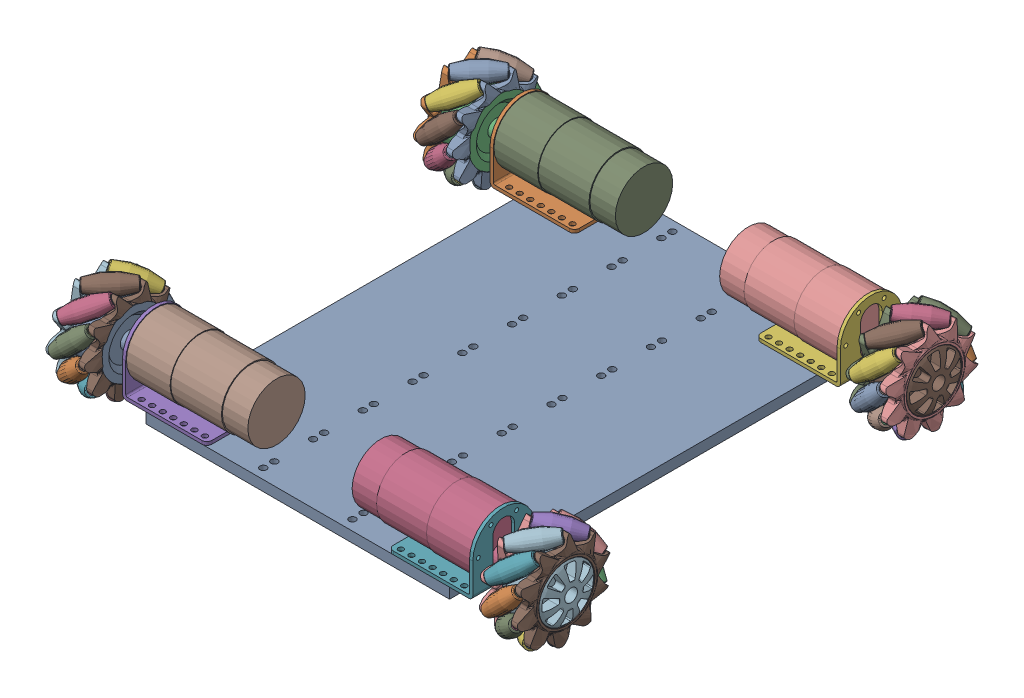
SolidWorks assembly ChassisRev2, configuration Default. Lengths in mm.
Overall size (295.62 86.39 309.14).
13 component instances, 4 part files, 32 mates.
Components (placement in the parent):
- BasePlateLayoutRev2-1: BasePlateLayoutRev2 [Default] at origin size (184.15 6.35 260.35)
- 37D bracket -1: 37D bracket  [Default] at (-106.2055 0 -111.4) size (51.2 39.6 37.6)
- Mecanum Wheel Right-1: Mecanum Wheel Right [Default] at (-111.8327 3.9469 -59.297) x (1 0 0) z (0 -0.102615 -0.994721) size (34.3 61.34 61.21)
- Motor - 37D - with encoder - 100_1 and 131_1-1: Motor - 37D - with encoder - 100_1 and 131_1 [Default] at (31.6055 20.8 111.4) x (0 0 -1) z (1 0 0) size (36.8 36.8 94.6)
- 37D bracket -2: 37D bracket  [Default] at (-106.2055 0 111.4) size (51.2 39.6 37.6)
- 37D bracket -3: 37D bracket  [Default] at (106.2055 0 -111.4) x (-1 0 0) z (0 0 -1) size (51.2 39.6 37.6)
- 37D bracket -4: 37D bracket  [Default] at (106.2055 0 111.4) x (-1 0 0) z (0 0 -1) size (51.2 39.6 37.6)
- Motor - 37D - with encoder - 100_1 and 131_1-2: Motor - 37D - with encoder - 100_1 and 131_1 [Default] at (-31.6055 20.8 111.4) x (0 0 1) z (-1 0 0) size (36.8 36.8 94.6)
- Motor - 37D - with encoder - 100_1 and 131_1-3: Motor - 37D - with encoder - 100_1 and 131_1 [Default] at (-31.6055 20.8 -111.4) x (0 0 1) z (-1 0 0) size (36.8 36.8 94.6)
- Motor - 37D - with encoder - 100_1 and 131_1-4: Motor - 37D - with encoder - 100_1 and 131_1 [Default] at (31.6055 20.8 -111.4) x (0 0 -1) z (1 0 0) size (36.8 36.8 94.6)
- Mecanum Wheel Right-2: Mecanum Wheel Right [Default] at (111.8327 -30.2853 -140.8668) x (-1 0 0) z (0 0.637998 0.770038) size (34.3 61.34 61.21)
- Mecanum Wheel Right-3: Mecanum Wheel Right [Default] at (111.8327 -34.6568 89.8655) x (-1 0 0) z (0 0.759736 0.650232) size (34.3 61.34 61.21)
- Mecanum Wheel Right-4: Mecanum Wheel Right [Default] at (-111.8327 2.6629 163.2437) x (1 0 0) z (0 -0.078013 -0.996952) size (34.3 61.34 61.21)
Mates (geometry in assembly coordinates):
- Concentric2: concentric aligned: cylinder of BasePlateLayoutRev2-1 through (-85.0055 -10.8755 -127) axis (0 1 0) radius 1.6; cylinder of 37D bracket -1 through (-85.0055 2 -127) axis (0 1 0) radius 1.6
- Concentric3: concentric aligned: cylinder of BasePlateLayoutRev2-1 through (-85.0055 -10.8755 -95.8) axis (0 1 0) radius 1.6; cylinder of 37D bracket -1 through (-85.0055 2 -95.8) axis (0 1 0) radius 1.6
- Concentric4: concentric aligned: cylinder of BasePlateLayoutRev2-1 through (-85.0055 -10.8755 95.8) axis (0 1 0) radius 1.6; cylinder of 37D bracket -2 through (-85.0055 2 95.8) axis (0 1 0) radius 1.6
- Concentric5: concentric aligned: cylinder of BasePlateLayoutRev2-1 through (-85.0055 -10.8755 127) axis (0 1 0) radius 1.6; cylinder of 37D bracket -2 through (-85.0055 2 127) axis (0 1 0) radius 1.6
- Concentric6: concentric aligned: cylinder of BasePlateLayoutRev2-1 through (85.0055 -10.8755 127) axis (0 1 0) radius 1.6; cylinder of 37D bracket -4 through (85.0055 2 127) axis (0 1 0) radius 1.6
- Concentric7: concentric aligned: cylinder of BasePlateLayoutRev2-1 through (85.0055 -10.8755 95.8) axis (0 1 0) radius 1.6; cylinder of 37D bracket -4 through (85.0055 2 95.8) axis (0 1 0) radius 1.6
- Concentric8: concentric aligned: cylinder of BasePlateLayoutRev2-1 through (85.0055 -10.8755 -95.8) axis (0 1 0) radius 1.6; cylinder of 37D bracket -3 through (85.0055 2 -95.8) axis (0 1 0) radius 1.6
- Concentric9: concentric aligned: cylinder of BasePlateLayoutRev2-1 through (85.0055 -10.8755 -127) axis (0 1 0) radius 1.6; cylinder of 37D bracket -3 through (85.0055 2 -127) axis (0 1 0) radius 1.6
- Coincident2: coincident anti-aligned: plane of BasePlateLayoutRev2-1 through (0 0 0) normal (0 1 0); plane of 37D bracket -2 through (-103.7055 0 130.2) normal (0 -1 0)
- Coincident3: coincident anti-aligned: plane of BasePlateLayoutRev2-1 through (0 0 0) normal (0 1 0); plane of 37D bracket -1 through (-103.7055 0 -92.6) normal (0 -1 0)
- Coincident4: coincident anti-aligned: plane of BasePlateLayoutRev2-1 through (0 0 0) normal (0 1 0); plane of 37D bracket -3 through (103.7055 0 -130.2) normal (0 -1 0)
- Coincident5: coincident anti-aligned: plane of BasePlateLayoutRev2-1 through (0 0 0) normal (0 1 0); plane of 37D bracket -4 through (103.7055 0 92.6) normal (0 -1 0)
- Concentric10: concentric aligned: cylinder of 37D bracket -1 through (-55.0045 7.3766 -103.65) axis (-1 0 0) radius 1.2044; cylinder of Motor - 37D - with encoder - 100_1 and 131_1-3 through (-104.2055 7.3766 -103.65) axis (-1 0 0) radius 1.25
- Concentric11: concentric aligned: cylinder of 37D bracket -1 through (-55.0045 7.3766 -119.15) axis (-1 0 0) radius 1.2044; cylinder of Motor - 37D - with encoder - 100_1 and 131_1-3 through (-104.2055 7.3766 -119.15) axis (-1 0 0) radius 1.25
- Concentric12: concentric aligned: cylinder of 37D bracket -2 through (-55.0045 7.3766 103.65) axis (-1 0 0) radius 1.2044; cylinder of Motor - 37D - with encoder - 100_1 and 131_1-2 through (-104.2055 7.3766 103.65) axis (-1 0 0) radius 1.25
- Concentric13: concentric aligned: cylinder of 37D bracket -2 through (-55.0045 7.3766 119.15) axis (-1 0 0) radius 1.2044; cylinder of Motor - 37D - with encoder - 100_1 and 131_1-2 through (-104.2055 7.3766 119.15) axis (-1 0 0) radius 1.25
- Coincident6: coincident anti-aligned: plane of 37D bracket -1 through (-104.2055 3 -92.6) normal (1 0 0); plane of Motor - 37D - with encoder - 100_1 and 131_1-3 through (-104.2055 20.8 -111.4) normal (-1 0 0)
- Coincident7: coincident anti-aligned: plane of 37D bracket -2 through (-104.2055 3 130.2) normal (1 0 0); plane of Motor - 37D - with encoder - 100_1 and 131_1-2 through (-104.2055 20.8 111.4) normal (-1 0 0)
- Concentric14: concentric aligned: cylinder of Motor - 37D - with encoder - 100_1 and 131_1-1 through (104.2055 7.3766 119.15) axis (1 0 0) radius 1.25; cylinder of 37D bracket -4 through (55.0045 7.3766 119.15) axis (1 0 0) radius 1.2044
- Concentric15: concentric aligned: cylinder of Motor - 37D - with encoder - 100_1 and 131_1-1 through (104.2055 7.3766 103.65) axis (1 0 0) radius 1.25; cylinder of 37D bracket -4 through (55.0045 7.3766 103.65) axis (1 0 0) radius 1.2044
- Coincident8: coincident anti-aligned: plane of Motor - 37D - with encoder - 100_1 and 131_1-1 through (104.2055 20.8 111.4) normal (1 0 0); plane of 37D bracket -4 through (104.2055 3 92.6) normal (-1 0 0)
- Concentric16: concentric aligned: cylinder of 37D bracket -3 through (55.0045 7.3766 -103.65) axis (1 0 0) radius 1.2044; cylinder of Motor - 37D - with encoder - 100_1 and 131_1-4 through (104.2055 7.3766 -103.65) axis (1 0 0) radius 1.25
- Concentric17: concentric aligned: cylinder of 37D bracket -3 through (55.0045 7.3766 -119.15) axis (1 0 0) radius 1.2044; cylinder of Motor - 37D - with encoder - 100_1 and 131_1-4 through (104.2055 7.3766 -119.15) axis (1 0 0) radius 1.25
- Coincident9: coincident anti-aligned: plane of 37D bracket -3 through (104.2055 3 -130.2) normal (-1 0 0); plane of Motor - 37D - with encoder - 100_1 and 131_1-4 through (104.2055 20.8 -111.4) normal (1 0 0)
- Concentric18: concentric: circle of Mecanum Wheel Right-1; circle of Motor - 37D - with encoder - 100_1 and 131_1-3
- Distance1: distance = 12.7 mm anti-aligned: plane of Mecanum Wheel Right-1 through (-113.5055 13.8 -111.4) normal (1 0 0); plane of Motor - 37D - with encoder - 100_1 and 131_1-3 through (-126.2055 13.8 -111.4) normal (-1 0 0)
- Concentric19: concentric: circle of Motor - 37D - with encoder - 100_1 and 131_1-2; circle of Mecanum Wheel Right-4
- Distance2: distance = 12.7 mm anti-aligned: plane of Mecanum Wheel Right-4 through (-113.5055 13.8 111.4) normal (1 0 0); plane of Motor - 37D - with encoder - 100_1 and 131_1-2 through (-126.2055 13.8 111.4) normal (-1 0 0)
- Concentric20: concentric: circle of Motor - 37D - with encoder - 100_1 and 131_1-1; circle of Mecanum Wheel Right-3
- Distance3: distance = 12.7 mm anti-aligned: plane of Mecanum Wheel Right-3 through (113.5055 13.8 111.4) normal (-1 0 0); plane of Motor - 37D - with encoder - 100_1 and 131_1-1 through (126.2055 13.8 111.4) normal (1 0 0)
- Concentric21: concentric: circle of Motor - 37D - with encoder - 100_1 and 131_1-4; circle of Mecanum Wheel Right-2
- Distance4: distance = 12.7 mm anti-aligned: plane of Mecanum Wheel Right-2 through (113.5055 13.8 -111.4) normal (-1 0 0); plane of Motor - 37D - with encoder - 100_1 and 131_1-4 through (126.2055 13.8 -111.4) normal (1 0 0)
